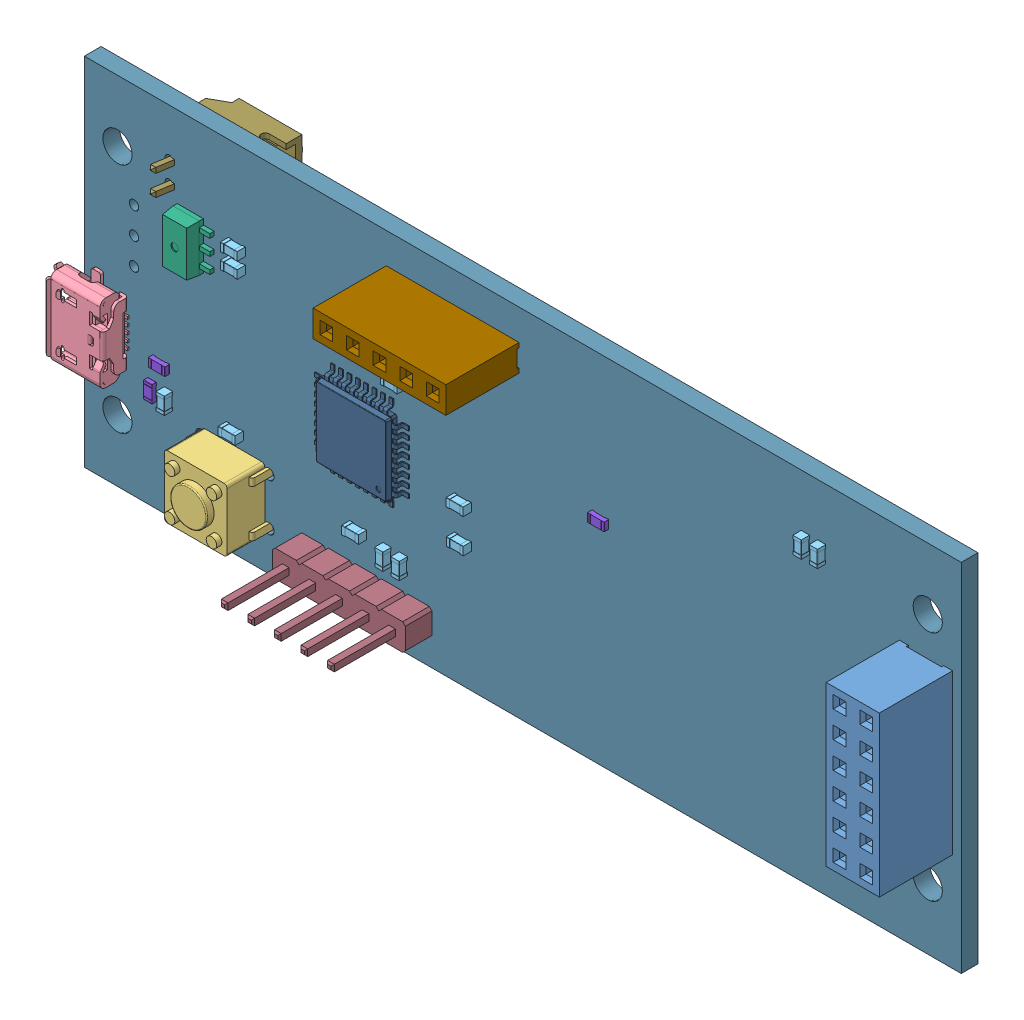
SolidWorks assembly FE2, configuration Default. Lengths in mm.
Overall size (84.97 34.05 15.09).
63 component instances, 14 part files, 0 mates.
Components (placement in the parent):
- PinSocket_2x06_P2.54mm_Vertical-1: PinSocket_2x06_P2.54mm_Vertical [Default] at (167.695 -48.915 1.65) size (5.08 15.24 10.1)
  - SOLID_6-1: SOLID_6 [Default] at origin size (5.08 15.24 10.1)
- U.FL_Hirose_U.FL-R-SMT-1_Vertical-1: U.FL_Hirose_U.FL-R-SMT-1_Vertical [Default] at (157.925 -58.85 -0.05) x (1 0 0) z (0 0 -1) size (3.1 3 1.25)
  - SOLID_10-1: SOLID_10 [Default] at origin size (3.1 3 1.25)
- SW_PUSH_6mm-1: SW_PUSH_6mm [Default] at (97.05 -64.1 1.65) size (7.17 6 7.8)
  - SOLID_3-1: SOLID_3 [Default] at origin size (7.17 6 7.8)
- USB_Micro-B_Molex_47346-0001-1: USB_Micro-B_Molex_47346-0001 [Default] at (88.55 -59.05 1.65) x (0 -1 0) z (0 0 1) size (7.98 5.42 2.94)
  - SOLID_7-1: SOLID_7 [Default] at origin size (7.98 5.42 2.94)
- C_0603_1608Metric-1: C_0603_1608Metric [Default] at (116.45 -65.05 1.65) x (0 -1 0) z (0 0 1) size (1.6 0.8 0.8)
  - SOLID_4-1: SOLID_4 [Default] at origin size (1.6 0.8 0.8)
- SOT-89-3-1: SOT-89-3 [Default] at (96.35 -48.25 1.65) x (-1 0 0) z (0 0 1) size (4 4.5 1.52)
  - SOLID_11-1: SOLID_11 [Default] at origin size (4 4.5 1.52)
- SOT-143-1: SOT-143 [Default] at (100 -58.65 -0.05) x (0 1 0) z (0 0 -1) size (2.8 2.9 1.2)
  - SOLID_12-1: SOLID_12 [Default] at origin size (2.8 2.9 1.2)
- R_0603_1608Metric-1: R_0603_1608Metric [Default] at (135.3 -51.95 1.65) x (-1 0 0) z (0 0 1) size (1.6 0.8 0.45)
  - SOLID_13-1: SOLID_13 [Default] at origin size (1.6 0.8 0.45)
- R_0603_1608Metric-2: R_0603_1608Metric [Default] at (93.3 -60.1 1.65) x (-1 0 0) z (0 0 1) size (1.6 0.8 0.45)
  - SOLID_13-1: SOLID_13 [Default] at origin size (1.6 0.8 0.45)
- R_0603_1608Metric-3: R_0603_1608Metric [Default] at (92.45 -62.6 1.65) x (0 1 0) z (0 0 1) size (1.6 0.8 0.45)
  - SOLID_13-1: SOLID_13 [Default] at origin size (1.6 0.8 0.45)
- R_0603_1608Metric-4: R_0603_1608Metric [Default] at (109.05 -65.95 -0.05) x (-1 0 0) z (0 0 -1) size (1.6 0.8 0.45)
  - SOLID_13-1: SOLID_13 [Default] at origin size (1.6 0.8 0.45)
- R_0603_1608Metric-5: R_0603_1608Metric [Default] at (114.45 -65.9 -0.05) x (1 0 0) z (0 0 -1) size (1.6 0.8 0.45)
  - SOLID_13-1: SOLID_13 [Default] at origin size (1.6 0.8 0.45)
- C_0603_1608Metric-2: C_0603_1608Metric [Default] at (94 -62.6 1.65) x (0 1 0) z (0 0 1) size (1.6 0.8 0.8)
  - SOLID_4-1: SOLID_4 [Default] at origin size (1.6 0.8 0.8)
- PinSocket_1x05_P2.54mm_Vertical-1: PinSocket_1x05_P2.54mm_Vertical [Default] at (126.25 -42.45 1.65) x (0 -1 0) z (0 0 1) size (2.54 12.7 10.1)
  - SOLID_5-1: SOLID_5 [Default] at origin size (2.54 12.7 10.1)
- TQFP-32_7x7mm_P0.8mm-1: TQFP-32_7x7mm_P0.8mm [Default] at (112.55 -56.325 1.65) x (-1 0 0) z (0 0 1) size (9 9 1.1)
  - SOLID-1: SOLID [Default] at origin size (9 9 1.1)
- L_0805_2012Metric-1: L_0805_2012Metric [Default] at (120.15 -48.55 1.65) size (2 1.25 1.25)
  - SOLID_2-1: SOLID_2 [Default] at origin size (2 1.25 1.25)
- JST_PH_S2B-PH-K_1x02_P2.00mm_Horizontal-1: JST_PH_S2B-PH-K_1x02_P2.00mm_Horizontal [Default] at (94 -42.8 -0.05) x (0 -1 0) z (0 0 -1) size (5.9 7.6 8.25)
  - SOLID_8-1: SOLID_8 [Default] at origin size (5.9 7.6 8.25)
- PinHeader_1x05_P2.54mm_Vertical-1: PinHeader_1x05_P2.54mm_Vertical [Default] at (107.75 -68.6 1.65) x (0 1 0) z (0 0 1) size (2.54 12.7 11.54)
  - SOLID_9-1: SOLID_9 [Default] at origin size (2.54 12.7 11.54)
- C_0603_1608Metric-3: C_0603_1608Metric [Default] at (148.15 -61.4 -0.05) x (-1 0 0) z (0 0 -1) size (1.6 0.8 0.8)
  - SOLID_4-1: SOLID_4 [Default] at origin size (1.6 0.8 0.8)
- C_0603_1608Metric-4: C_0603_1608Metric [Default] at (148.15 -62.95 -0.05) x (-1 0 0) z (0 0 -1) size (1.6 0.8 0.8)
  - SOLID_4-1: SOLID_4 [Default] at origin size (1.6 0.8 0.8)
- C_0603_1608Metric-5: C_0603_1608Metric [Default] at (154.9 -44.05 1.65) x (0 1 0) z (0 0 1) size (1.6 0.8 0.8)
  - SOLID_4-1: SOLID_4 [Default] at origin size (1.6 0.8 0.8)
- C_0603_1608Metric-6: C_0603_1608Metric [Default] at (156.45 -44.05 1.65) x (0 1 0) z (0 0 1) size (1.6 0.8 0.8)
  - SOLID_4-1: SOLID_4 [Default] at origin size (1.6 0.8 0.8)
- C_0603_1608Metric-7: C_0603_1608Metric [Default] at (100.55 -46.75 1.65) size (1.6 0.8 0.8)
  - SOLID_4-1: SOLID_4 [Default] at origin size (1.6 0.8 0.8)
- C_0603_1608Metric-8: C_0603_1608Metric [Default] at (100.55 -48.25 1.65) size (1.6 0.8 0.8)
  - SOLID_4-1: SOLID_4 [Default] at origin size (1.6 0.8 0.8)
- C_0603_1608Metric-9: C_0603_1608Metric [Default] at (122.15 -57.1 1.65) size (1.6 0.8 0.8)
  - SOLID_4-1: SOLID_4 [Default] at origin size (1.6 0.8 0.8)
- C_0603_1608Metric-10: C_0603_1608Metric [Default] at (122.16 -60.35 1.65) size (1.6 0.8 0.8)
  - SOLID_4-1: SOLID_4 [Default] at origin size (1.6 0.8 0.8)
- C_0603_1608Metric-11: C_0603_1608Metric [Default] at (114.9 -65.05 1.65) x (0 -1 0) z (0 0 1) size (1.6 0.8 0.8)
  - SOLID_4-1: SOLID_4 [Default] at origin size (1.6 0.8 0.8)
- C_0603_1608Metric-12: C_0603_1608Metric [Default] at (115.85 -50.1 1.65) x (-1 0 0) z (0 0 1) size (1.6 0.8 0.8)
  - SOLID_4-1: SOLID_4 [Default] at origin size (1.6 0.8 0.8)
- C_0603_1608Metric-13: C_0603_1608Metric [Default] at (116.55 -48.55 1.65) x (-1 0 0) z (0 0 1) size (1.6 0.8 0.8)
  - SOLID_4-1: SOLID_4 [Default] at origin size (1.6 0.8 0.8)
- C_0603_1608Metric-14: C_0603_1608Metric [Default] at (100.35 -62.1 1.65) x (-1 0 0) z (0 0 1) size (1.6 0.8 0.8)
  - SOLID_4-1: SOLID_4 [Default] at origin size (1.6 0.8 0.8)
- C_0603_1608Metric-15: C_0603_1608Metric [Default] at (112.15 -64.4 1.65) x (-1 0 0) z (0 0 1) size (1.6 0.8 0.8)
  - SOLID_4-1: SOLID_4 [Default] at origin size (1.6 0.8 0.8)
- COMPOUND-1: COMPOUND [Default] at origin size (83.85 34.05 1.6)
